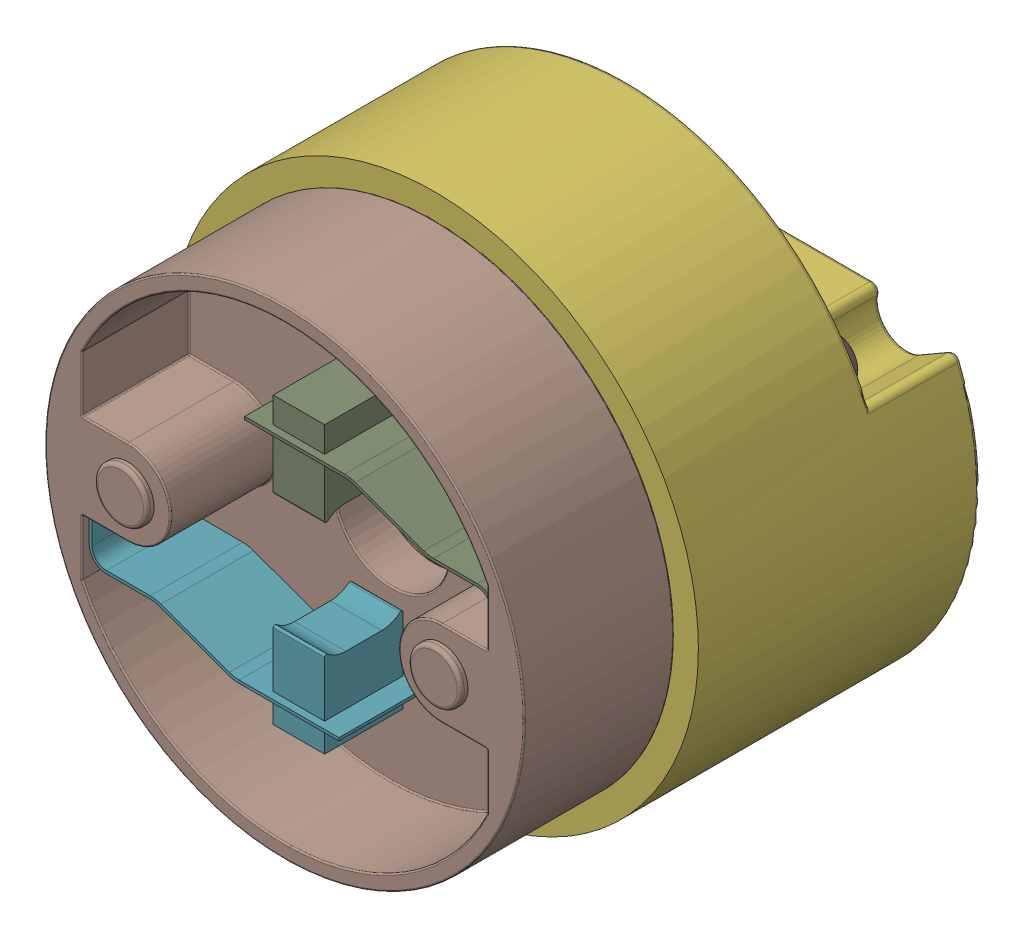
SolidWorks assembly Cap, configuration Default. Lengths in mm.
Overall size (37 37 30.95).
10 component instances, 5 part files, 0 mates.
Components (placement in the parent):
- JST-XH-4POS-VERT-1: JST-XH-4POS-VERT [Default] at (2.8 12.25 -75.95) x (1 0 0) z (0 0 -1) size (12.4 5.75 10.4)
  - Plastic-1: Plastic [Default] at (0 -2.875 0) size (12.4 5.75 7)
  - Pin-1: Pin [Default] at (3.75 -0.525 1.6) size (0.64 0.64 10)
  - Pin-2: Pin [Default] at (-3.75 -0.525 1.6) size (0.64 0.64 10)
  - Pin-3: Pin [Default] at (-1.25 -0.525 1.6) size (0.64 0.64 10)
  - Pin-4: Pin [Default] at (1.25 -0.525 1.6) size (0.64 0.64 10)
- Encoder Cap-1: Encoder Cap [Default] at origin size (37 37 19.95)
- Stopper-1: Stopper [Default] at origin size (34.25 33.6 11)
- Screw-1: Screw [Default] at (41.264 8.1646 3.9905) x (-0.882398 0 0.470504) z (0 1 0) size (5.37 7.47 3.5)
- Screw-2: Screw [Default] at (-41.264 -8.1646 3.9905) x (0.882398 0 0.470504) z (0 -1 0) size (5.37 7.47 3.5)
